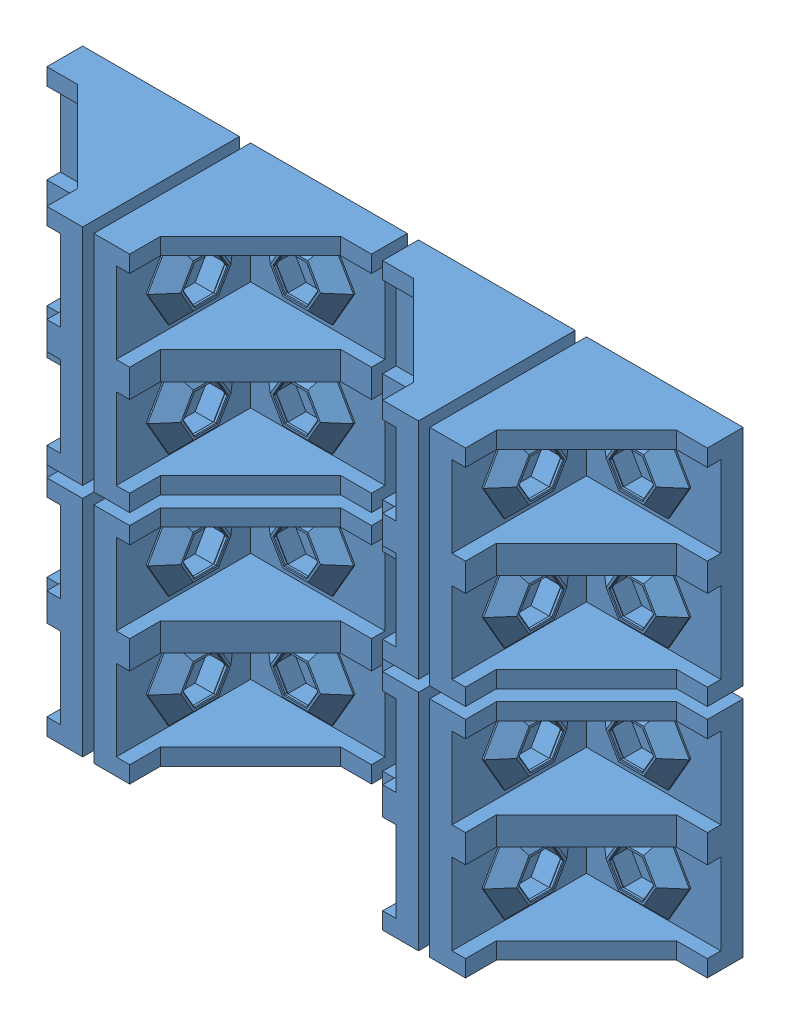
SolidWorks assembly window-bracket-plate-2x, configuration Default. Lengths in mm.
Overall size (118 106.25 62.64).
8 component instances, 1 part files, 24 mates.
Components (placement in the parent):
- window-bracket-dual-1: window-bracket-dual [Default] at (-121 -143.1346 163.4567) x (0 0.866025 -0.5) z (0 0.5 0.866025) size (48.64 28 44.25)
- window-bracket-dual-3: window-bracket-dual [Default] at (-121 -101.1346 163.4567) x (0 0.866025 -0.5) z (0 0.5 0.866025) size (48.64 28 44.25)
- window-bracket-dual-4: window-bracket-dual [Default] at (61 143.1346 163.4567) x (0 -0.866025 -0.5) z (0 -0.5 0.866025) size (48.64 28 44.25)
- window-bracket-dual-5: window-bracket-dual [Default] at (61 101.1346 163.4567) x (0 -0.866025 -0.5) z (0 -0.5 0.866025) size (48.64 28 44.25)
- window-bracket-dual-8: window-bracket-dual [Default] at (121 143.1346 163.4567) x (0 -0.866025 -0.5) z (0 -0.5 0.866025) size (48.64 28 44.25)
- window-bracket-dual-9: window-bracket-dual [Default] at (121 101.1346 163.4567) x (0 -0.866025 -0.5) z (0 -0.5 0.866025) size (48.64 28 44.25)
- window-bracket-dual-10: window-bracket-dual [Default] at (-61 -143.1346 163.4567) x (0 0.866025 -0.5) z (0 0.5 0.866025) size (48.64 28 44.25)
- window-bracket-dual-11: window-bracket-dual [Default] at (-61 -101.1346 163.4567) x (0 0.866025 -0.5) z (0 0.5 0.866025) size (48.64 28 44.25)
Mates (geometry in assembly coordinates):
- Coincident1: coincident aligned: plane of window-bracket-dual-1 through (-27.9359 -143.1346 90) normal (1 0 0); plane of window-bracket-dual-3 through (-27.9359 -101.1346 90) normal (1 0 0)
- Distance3: distance = 2 mm anti-aligned: plane of window-bracket-dual-3 through (-31 -101.1346 90) normal (1 0 0); plane of window-bracket-dual-4 through (-29 143.1346 90) normal (-1 0 0)
- Distance1: distance = 2 mm anti-aligned: plane of window-bracket-dual-3 through (-59 1 28) normal (0 -1 0); plane of window-bracket-dual-1 through (-59 -1 28) normal (0 1 0)
- Coincident5: coincident aligned: plane of window-bracket-dual-4 through (64.0641 143.1346 0) normal (0 0 -1); plane of window-bracket-dual-3 through (-117.9359 -101.1346 0) normal (0 0 -1)
- Coincident6: coincident aligned: plane of window-bracket-dual-3 through (-55.9359 1 28) normal (0 -1 0); plane of window-bracket-dual-4 through (2.0641 1 28) normal (0 -1 0)
- Coincident7: coincident aligned: plane of window-bracket-dual-1 through (-117.9359 -143.1346 0) normal (0 0 -1); plane of window-bracket-dual-3 through (-117.9359 -101.1346 0) normal (0 0 -1)
- Distance6: distance = 2 mm anti-aligned: plane of window-bracket-dual-5 through (-29 101.1346 90) normal (-1 0 0); plane of window-bracket-dual-1 through (-31 -143.1346 90) normal (1 0 0)
- Coincident13: coincident aligned: plane of window-bracket-dual-1 through (-55.9359 -1 28) normal (0 1 0); plane of window-bracket-dual-5 through (2.0641 -1 28) normal (0 1 0)
- Coincident14: coincident aligned: plane of window-bracket-dual-1 through (-117.9359 -143.1346 0) normal (0 0 -1); plane of window-bracket-dual-5 through (64.0641 101.1346 0) normal (0 0 -1)
- Coincident19: coincident aligned: plane of window-bracket-dual-4 through (2.0641 41 28) normal (0 1 0); plane of window-bracket-dual-8 through (62.0641 41 28) normal (0 1 0)
- Coincident20: coincident aligned: plane of window-bracket-dual-4 through (64.0641 143.1346 0) normal (0 0 -1); plane of window-bracket-dual-8 through (124.0641 143.1346 0) normal (0 0 -1)
- Coincident22: coincident aligned: plane of window-bracket-dual-5 through (64.0641 101.1346 0) normal (0 0 -1); plane of window-bracket-dual-9 through (124.0641 101.1346 0) normal (0 0 -1)
- Coincident23: coincident aligned: plane of window-bracket-dual-5 through (2.0641 -1 28) normal (0 1 0); plane of window-bracket-dual-9 through (62.0641 -1 28) normal (0 1 0)
- Symmetric2: symmetric aligned: plane of ? through (2.0641 1 28) normal (0 -1 0); plane of ? through (2.0641 -1 28) normal (0 1 0)
- Coincident34: coincident aligned: plane of window-bracket-dual-8 through (124.0641 143.1346 0) normal (0 0 -1); plane of window-bracket-dual-11 through (-57.9359 -101.1346 0) normal (0 0 -1)
- Distance10: distance = 2 mm anti-aligned: plane of window-bracket-dual-8 through (31 143.1346 90) normal (-1 0 0); plane of window-bracket-dual-11 through (29 -101.1346 90) normal (1 0 0)
- Concentric1: concentric anti-aligned: cylinder of window-bracket-dual-8 through (198.9281 31 15) axis (-1 0 0) radius 2; cylinder of window-bracket-dual-11 through (-132.7999 31 15) axis (1 0 0) radius 2
- Distance11: distance = 2 mm anti-aligned: plane of window-bracket-dual-4 through (-1 41 28) normal (1 0 0); plane of window-bracket-dual-11 through (1 1 28) normal (-1 0 0)
- Distance12: distance = 2 mm anti-aligned: plane of window-bracket-dual-10 through (29 -143.1346 90) normal (1 0 0); plane of window-bracket-dual-9 through (31 101.1346 90) normal (-1 0 0)
- Coincident38: coincident aligned: plane of window-bracket-dual-9 through (124.0641 101.1346 0) normal (0 0 -1); plane of window-bracket-dual-10 through (-57.9359 -143.1346 0) normal (0 0 -1)
- Concentric2: concentric anti-aligned: cylinder of window-bracket-dual-9 through (198.9281 -11 15) axis (-1 0 0) radius 2; cylinder of window-bracket-dual-10 through (-132.7999 -11 15) axis (1 0 0) radius 2
- Distance13: distance = 2 mm anti-aligned: plane of window-bracket-dual-5 through (-1 -1 28) normal (1 0 0); plane of window-bracket-dual-10 through (1 -41 28) normal (-1 0 0)
- Coincident39: coincident anti-aligned: plane of ? through (-117.9359 -101.1346 0) normal (0 0 -1)
- Symmetric3: symmetric aligned: plane of window-bracket-dual-4 through (-1 41 28) normal (1 0 0); plane of window-bracket-dual-11 through (1 1 28) normal (-1 0 0); plane of assembly
